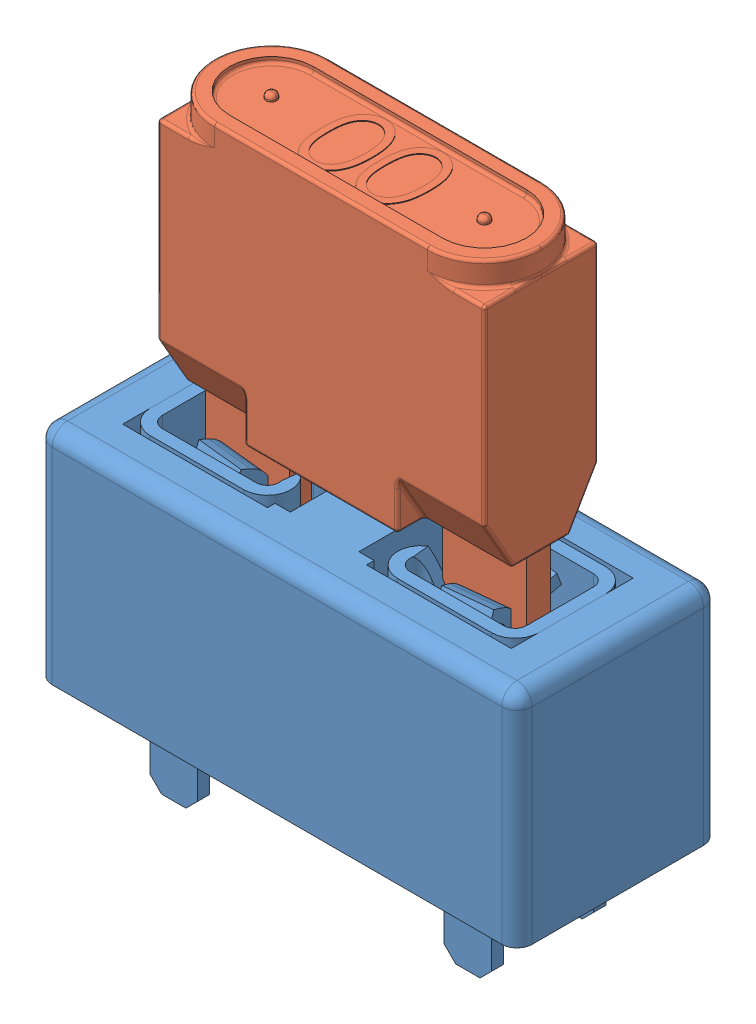
SolidWorks assembly Keystone 3568 with fuse, configuration Default. Lengths in mm.
Overall size (16 20.23 6.73).
2 component instances, 2 part files, 6 mates.
Components (placement in the parent):
- keystone-PN3568-1: keystone-PN3568 [Default] at (4.59 5.0089 -2.2255) size (16 10.16 6.73)
- MINI 297 or ATM Fuse-1: MINI 297 or ATM Fuse [Default] at (5.6896 8.636 -1.905) x (1 0 0) z (0 1 0) size (10.92 4 16.3)
Mates (geometry in assembly coordinates):
- Width1: width anti-aligned: plane of keystone-PN3568-1 through (-0.381 14.053 -0.7874) normal (1 0 0); plane of MINI 297 or ATM Fuse-1 through (11.7602 14.053 -3.0226) normal (-1 0 0); plane of keystone-PN3568-1 through (0.3396 7.823 -1.5) normal (-1 0 0); plane of MINI 297 or ATM Fuse-1 through (11.0396 7.823 -1.5) normal (1 0 0)
- Width2: width anti-aligned: plane of keystone-PN3568-1 through (11.3792 14.053 -3.4036) normal (0 0 1); plane of MINI 297 or ATM Fuse-1 through (11.3792 14.053 -0.4064) normal (0 0 -1); plane of keystone-PN3568-1 through (11.0396 7.823 -2.31) normal (0 0 -1); plane of MINI 297 or ATM Fuse-1 through (11.0396 7.823 -1.5) normal (0 0 1)
- Distance1: distance = 1.27 mm anti-aligned: plane of keystone-PN3568-1 through (13.1826 7.366 -4.7625) normal (0 1 0); plane of MINI 297 or ATM Fuse-1 through (5.6896 8.636 -1.905) normal (0 -1 0)
- Coincident1: coincident aligned: plane of keystone-PN3568-1 through (0 7.366 0) normal (0 0 1)
- Coincident2: coincident anti-aligned: plane of keystone-PN3568-1 through (0 1.016 0) normal (-1 0 0)
- Coincident3: coincident anti-aligned: plane of keystone-PN3568-1 through (13.1826 0 -4.7625) normal (0 -1 0)
